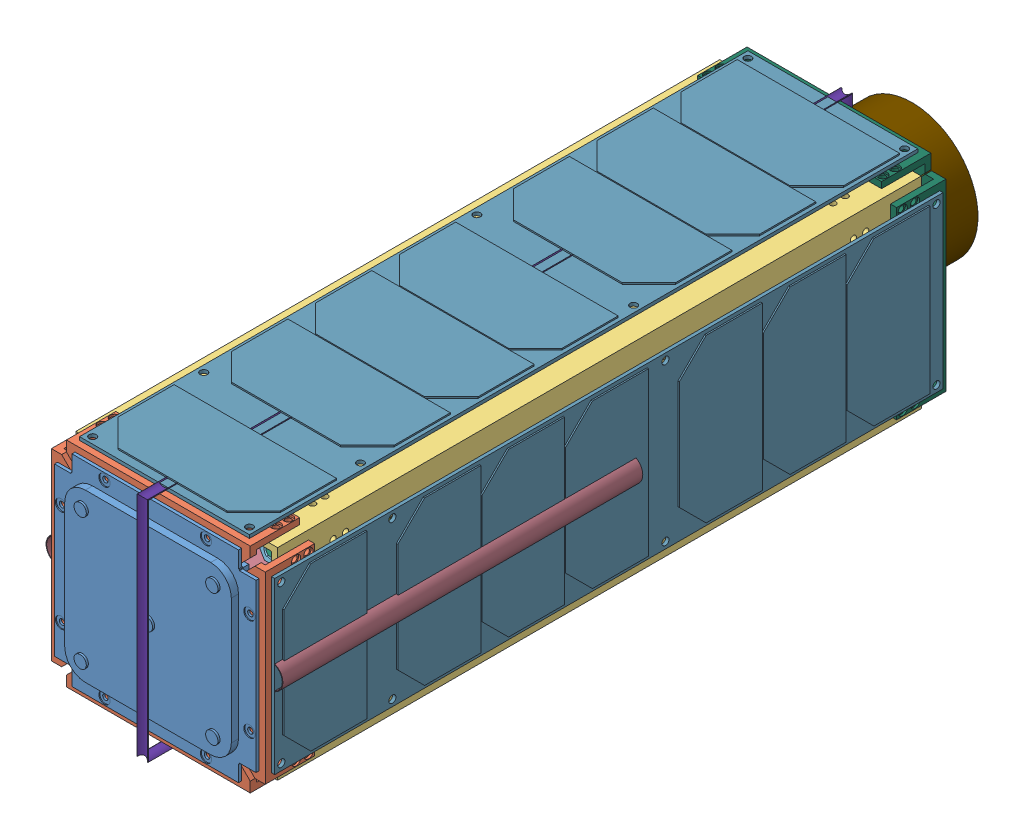
SolidWorks assembly RADIO Deconstructed2, configuration Default. Lengths in mm.
Overall size (115.59 110.99 374.49).
77 component instances, 18 part files, 143 mates.
Components (placement in the parent):
- Nanocom Antenna-1: Nanocom Antenna [Default] at (54.7327 27.087 80.9297) size (98 98 11)
- Top Sipport-1: Top Sipport [Default] at (83.9034 50.4516 80.9297) x (0 -1 0) z (0 0 -1) size (89.4 11 24)
- Top Sipport-2: Top Sipport [Default] at (-15.8818 37.5538 80.9297) x (0 1 0) z (0 0 -1) size (89.4 11 24)
- Top Sipport-3: Top Sipport [Default] at (27.5619 93.8953 80.9297) x (1 0 0) z (0 0 -1) size (89.4 11 24)
- Top Sipport-4: Top Sipport [Default] at (40.4598 -5.8899 80.9297) x (-1 0 0) z (0 0 -1) size (89.4 11 24)
- Support-1: Support [Default] at (-14.9892 90.3455 -221.7132) x (0 -1 0) z (1 0 0) size (18 313 15)
- Support-2: Support [Default] at (-12.332 -4.9973 -221.7132) x (1 0 0) z (0 1 0) size (18 313 15)
- Support-3: Support [Default] at (80.3537 93.0027 -221.7132) x (-1 0 0) z (0 -1 0) size (18 313 15)
- Support-4: Support [Default] at (83.0108 -2.3402 -221.7132) x (0 1 0) z (-1 0 0) size (18 313 15)
- Top Plate2-1: Top Plate2 [Default] at (13.317 21.6849 56.9297) x (-1 0 0) z (0 0 -1) size (92 92 23)
- Nut-1: Nut [Default] at (-1.4892 79.5027 56.9297) size (11.55 10 5.32)
- Nut-2: Nut [Default] at (69.5108 8.5027 56.9297) x (0.821931 0.569587 0) z (0 0 1) size (11.55 10 5.32)
- Nut-3: Nut [Default] at (69.5108 79.5027 56.9297) size (11.55 10 5.32)
- Nut-4: Nut [Default] at (-1.4892 8.5027 56.9297) size (11.55 10 5.32)
- Threaded Rod2-1: Threaded Rod2 [Default] at (69.5108 8.5027 -231.0703) size (6.4 7.01 294.26)
- Threaded Rod2-2: Threaded Rod2 [Default] at (-1.4892 8.5027 -231.0703) size (6.4 7.01 294.26)
- Threaded Rod2-3: Threaded Rod2 [Default] at (-1.4892 79.5027 -231.0703) size (6.4 7.01 294.26)
- Threaded Rod2-4: Threaded Rod2 [Default] at (69.5108 79.5027 -231.0703) size (6.4 7.01 294.26)
- Mid Plate-1: Mid Plate [Default] at (4.649 54.0261 25.9297) size (86 86 3)
- Nut-5: Nut [Default] at (-1.4892 8.5027 20.9297) x (0.999286 -0.037791 0) z (0 0 1) size (11.55 10 5.32)
- Nut-6: Nut [Default] at (-1.4892 8.5027 28.9297) size (11.55 10 5.32)
- Nut-7: Nut [Default] at (69.5108 8.5027 28.9297) size (11.55 10 5.32)
- Nut-8: Nut [Default] at (69.5108 8.5027 20.9297) x (0.921379 0.388666 0) z (0 0 1) size (11.55 10 5.32)
- Nut-9: Nut [Default] at (69.5108 79.5027 28.9297) size (11.55 10 5.32)
- Nut-10: Nut [Default] at (-1.4892 79.5027 28.9297) size (11.55 10 5.32)
- Nut-11: Nut [Default] at (69.5108 79.5027 20.9297) x (0.963517 0.267648 0) z (0 0 1) size (11.55 10 5.32)
- Nut-12: Nut [Default] at (-1.4892 79.5027 20.9297) x (0.997929 0.06432 0) z (0 0 1) size (11.55 10 5.32)
- SDR-1: SDR [Default] at (37.1692 34.198 30.9297) size (65 40 16.8)
- TTC Radio-1: TTC Radio [Default] at (48.3672 78.5027 28.9297) x (0 1 0) z (0 0 1) size (19.7 16 5)
- Raspberry Pi-1: Raspberry Pi [Default] at (63.5108 49.6464 -55.0703) size (66 30.48 5)
- TTC Circuit-1: TTC Circuit [Default] at (24.4431 25.9578 10.9297) size (80 50 10)
- Battery-1: Battery [Default] at (21.7415 31.358 -37.0703) size (70.1 42.59 38.1)
- Tape Antenna-3: Tape Antenna [Default] at (-17.3053 44.2096 -97.0703) x (-0.035253 -0.999378 0) z (0 0 1) size (11.67 4.21 175)
- Tape Antenna-4: Tape Antenna [Default] at (85.299 43.4652 -97.0703) x (0.030207 0.999544 0) z (0 0 1) size (11.67 4.21 175)
- Mid Plate-2: Mid Plate [Default] at (4.649 54.0261 7.9297) size (86 86 3)
- Nut-13: Nut [Default] at (-1.4892 8.5027 10.9297) size (11.55 10 5.32)
- Nut-14: Nut [Default] at (69.5108 79.5027 10.9297) size (11.55 10 5.32)
- Nut-15: Nut [Default] at (-1.4892 8.5027 2.9297) size (11.55 10 5.32)
- Nut-16: Nut [Default] at (-1.4892 79.5027 10.9297) size (11.55 10 5.32)
- Nut-17: Nut [Default] at (-1.4892 79.5027 2.9297) size (11.55 10 5.32)
- Nut-18: Nut [Default] at (69.5108 8.5027 2.9297) size (11.55 10 5.32)
- Nut-19: Nut [Default] at (69.5108 8.5027 10.9297) size (11.55 10 5.32)
- Nut-20: Nut [Default] at (69.5108 79.5027 2.9297) size (11.55 10 5.32)
- Mid Plate-3: Mid Plate [Default] at (4.649 54.0261 -40.0703) size (86 86 3)
- Nut-21: Nut [Default] at (69.5108 79.5027 -37.0703) size (11.55 10 5.32)
- Nut-22: Nut [Default] at (-1.4892 8.5027 -40.0703) x (-0.923728 -0.383049 0) z (0 0 -1) size (11.55 10 5.32)
- Nut-23: Nut [Default] at (-1.4892 79.5027 -40.0703) x (-0.923728 -0.383049 0) z (0 0 -1) size (11.55 10 5.32)
- Nut-24: Nut [Default] at (69.5108 8.5027 -37.0703) size (11.55 10 5.32)
- Nut-25: Nut [Default] at (69.5108 79.5027 -40.0703) x (-0.923728 -0.383049 0) z (0 0 -1) size (11.55 10 5.32)
- Nut-26: Nut [Default] at (69.5108 8.5027 -40.0703) x (-0.923728 -0.383049 0) z (0 0 -1) size (11.55 10 5.32)
- Nut-27: Nut [Default] at (-1.4892 8.5027 -37.0703) size (11.55 10 5.32)
- Nut-28: Nut [Default] at (-1.4892 79.5027 -37.0703) size (11.55 10 5.32)
- Nut-29: Nut [Default] at (-1.4892 8.5027 -63.0703) size (11.55 10 5.32)
- Nut-30: Nut [Default] at (69.5108 79.5027 -63.0703) size (11.55 10 5.32)
- Nut-31: Nut [Default] at (69.5108 8.5027 -63.0703) size (11.55 10 5.32)
- Nut-32: Nut [Default] at (-1.4892 8.5027 -55.0703) size (11.55 10 5.32)
- Nut-33: Nut [Default] at (-1.4892 79.5027 -55.0703) size (11.55 10 5.32)
- Nut-34: Nut [Default] at (69.5108 8.5027 -55.0703) size (11.55 10 5.32)
- Nut-35: Nut [Default] at (-1.4892 79.5027 -63.0703) size (11.55 10 5.32)
- Nut-36: Nut [Default] at (69.5108 79.5027 -55.0703) size (11.55 10 5.32)
- Mid Plate-4: Mid Plate [Default] at (4.649 54.0261 -58.0703) size (86 86 3)
- Top Plate2-2: Top Plate2 [Default] at (54.7047 21.6849 -226.0703) size (92 92 23)
- Nut-37: Nut [Default] at (69.5108 8.5027 -226.0703) x (-0.923728 -0.383049 0) z (0 0 -1) size (11.55 10 5.32)
- Nut-38: Nut [Default] at (69.5108 79.5027 -226.0703) x (-0.923728 -0.383049 0) z (0 0 -1) size (11.55 10 5.32)
- Nut-39: Nut [Default] at (-1.4892 8.5027 -226.0703) x (-0.923728 -0.383049 0) z (0 0 -1) size (11.55 10 5.32)
- Nut-40: Nut [Default] at (-1.4892 79.5027 -226.0703) x (-0.923728 -0.383049 0) z (0 0 -1) size (11.55 10 5.32)
- 3U Panel-1: 3U Panel [Default] at (-17.9892 -8.6653 1.9441) x (0 -1 0) z (-1 0 0) size (82.6 325 2.3)
- 3U Panel-5: 3U Panel [Default] at (86.6788 -7.9973 1.9441) x (1 0 0) z (0 -1 0) size (82.6 325 2.3)
- 3U Panel-6: 3U Panel [Default] at (86.0108 96.6707 1.9441) x (0 1 0) z (1 0 0) size (82.6 325 2.3)
- 3U Panel-7: 3U Panel [Default] at (-18.6571 96.0027 1.9441) x (-1 0 0) z (0 1 0) size (82.6 325 2.3)
- Top Support Solar Panel-1: Top Support Solar Panel [Default] at (27.5619 -3.8899 -250.0703) size (89.4 13 24)
- Top Support Solar Panel-2: Top Support Solar Panel [Default] at (81.9034 37.5538 -250.0703) x (0 1 0) z (0 0 1) size (89.4 13 24)
- Top Support Solar Panel-3: Top Support Solar Panel [Default] at (40.4598 91.8953 -250.0703) x (-1 0 0) z (0 0 1) size (89.4 13 24)
- Top Support Solar Panel-4: Top Support Solar Panel [Default] at (-13.8818 50.4516 -250.0703) x (0 -1 0) z (0 0 1) size (89.4 13 24)
- 1U Panel-1: 1U Panel [Default] at (10.1282 49.1305 -250.0703) x (-1 0 0) z (0 0 -1) size (98 98 2.3)
- Undeployed Boom-1: Undeployed Boom [Default] at (33.6808 70.7812 -106.8653) x (0 0 -1) z (1 0 0) size (342.69 110.69 5.53)
- Mass-1: Mass [Default] at (33.6036 44.7293 -286.0703) size (64 64 36)
Mates (geometry in assembly coordinates):
- Coincident1: coincident: circle of Nanocom Antenna-1; circle of Top Sipport-4
- Coincident2: coincident: circle of Nanocom Antenna-1; circle of Top Sipport-4
- Coincident3: coincident: circle of Nanocom Antenna-1; circle of Top Sipport-2
- Coincident4: coincident: circle of Nanocom Antenna-1; circle of Top Sipport-2
- Coincident5: coincident: circle of Nanocom Antenna-1; circle of Top Sipport-3
- Coincident6: coincident: circle of Nanocom Antenna-1; circle of Top Sipport-3
- Coincident7: coincident: circle of Nanocom Antenna-1; circle of Top Sipport-1
- Coincident8: coincident: circle of Nanocom Antenna-1; circle of Top Sipport-1
- Coincident9: coincident: circle of Top Sipport-2; circle of Support-1
- Coincident10: coincident: circle of Top Sipport-3; circle of Support-1
- Coincident11: coincident: circle of Top Sipport-3; circle of Support-3
- Coincident12: coincident: circle of Top Sipport-1; circle of Support-3
- Coincident13: coincident: circle of Top Sipport-2; circle of Support-2
- Coincident14: coincident: circle of Top Sipport-4; circle of Support-2
- Coincident16: coincident: circle of Top Sipport-4; circle of Support-4
- Coincident17: coincident: circle of Top Sipport-1; circle of Support-4
- Coincident20: coincident: circle of Support-1; circle of Top Plate2-1
- Coincident21: coincident: circle of Support-2; circle of Top Plate2-1
- Coincident22: coincident: circle of Top Plate2-1; circle of Nut-3
- Coincident23: coincident: circle of Top Plate2-1; circle of Nut-1
- Coincident24: coincident: circle of Top Plate2-1; circle of Nut-4
- Coincident25: coincident: circle of Top Plate2-1; circle of Nut-2
- Concentric1: concentric: circle of Top Plate2-1; circle of Threaded Rod2-1
- Coincident26: coincident: plane of Nut-2 through (69.5108 8.5027 61.9297) normal (0 0 1); plane of Threaded Rod2-1 through (69.5108 8.5027 61.9297) normal (0 0 1)
- Concentric2: concentric: circle of Top Plate2-1; circle of Threaded Rod2-4
- Coincident27: coincident: plane of Nut-3 through (69.5108 79.5027 61.9297) normal (0 0 1); plane of Threaded Rod2-4 through (69.5108 79.5027 61.9297) normal (0 0 1)
- Concentric3: concentric: circle of Top Plate2-1; circle of Threaded Rod2-2
- Coincident28: coincident: plane of Nut-4 through (-1.4892 8.5027 61.9297) normal (0 0 1); plane of Threaded Rod2-2 through (-1.4892 8.5027 61.9297) normal (0 0 1)
- Concentric4: concentric: circle of Top Plate2-1; circle of Threaded Rod2-3
- Coincident29: coincident: plane of Nut-1 through (-1.4892 79.5027 61.9297) normal (0 0 1); plane of Threaded Rod2-3 through (-1.4892 79.5027 61.9297) normal (0 0 1)
- Concentric5: concentric: circle of Threaded Rod2-4; circle of Mid Plate-1
- Concentric6: concentric: circle of Threaded Rod2-2; circle of Mid Plate-1
- Concentric7: concentric: circle of Threaded Rod2-2; circle of Nut-6
- Coincident30: coincident: plane of Mid Plate-1 through (4.649 54.0261 28.9297) normal (0 0 1); plane of Nut-6 through (-1.4892 8.5027 28.9297) normal (0 0 -1)
- Concentric8: concentric: circle of Threaded Rod2-2; circle of Nut-5
- Coincident31: coincident: plane of Mid Plate-1 through (4.649 54.0261 25.9297) normal (0 0 -1); plane of Nut-5 through (-1.4892 8.5027 25.9297) normal (0 0 1)
- Concentric9: concentric: circle of Threaded Rod2-1; circle of Nut-7
- Coincident32: coincident: plane of Mid Plate-1 through (4.649 54.0261 28.9297) normal (0 0 1); plane of Nut-7 through (69.5108 8.5027 28.9297) normal (0 0 -1)
- Concentric10: concentric: circle of Threaded Rod2-1; circle of Nut-8
- Coincident33: coincident: plane of Mid Plate-1 through (4.649 54.0261 25.9297) normal (0 0 -1); plane of Nut-8 through (69.5108 8.5027 25.9297) normal (0 0 1)
- Concentric11: concentric: circle of Threaded Rod2-4; circle of Nut-9
- Coincident34: coincident: plane of Mid Plate-1 through (4.649 54.0261 28.9297) normal (0 0 1); plane of Nut-9 through (69.5108 79.5027 28.9297) normal (0 0 -1)
- Concentric12: concentric: circle of Threaded Rod2-3; circle of Nut-10
- Coincident35: coincident: plane of Mid Plate-1 through (4.649 54.0261 28.9297) normal (0 0 1); plane of Nut-10 through (-1.4892 79.5027 28.9297) normal (0 0 -1)
- Concentric13: concentric: circle of Threaded Rod2-4; circle of Nut-11
- Coincident36: coincident: plane of Mid Plate-1 through (4.649 54.0261 25.9297) normal (0 0 -1); plane of Nut-11 through (69.5108 79.5027 25.9297) normal (0 0 1)
- Concentric14: concentric: circle of Threaded Rod2-3; circle of Nut-12
- Coincident37: coincident: plane of Mid Plate-1 through (4.649 54.0261 25.9297) normal (0 0 -1); plane of Nut-12 through (-1.4892 79.5027 25.9297) normal (0 0 1)
- Distance1: distance = 25 mm: plane of Mid Plate-1 through (4.649 54.0261 28.9297) normal (0 0 1); plane of Top Plate2-1 through (13.317 21.6849 53.9297) normal (0 0 -1)
- Coincident39: coincident: plane of Mid Plate-1 through (4.649 54.0261 28.9297) normal (0 0 1); plane of SDR-1 through (37.1692 34.198 28.9297) normal (0 0 -1)
- Distance4: distance = 12 mm: line of SDR-1 through (65.0108 16.0027 28.9297) axis (0 1 0); line of Mid Plate-1 through (77.0108 4.0027 28.9297) axis (0 1 0)
- Distance5: distance = 15 mm: line of SDR-1 through (0.0108 16.0027 28.9297) axis (1 0 0); line of Mid Plate-1 through (-5.9892 1.0027 28.9297) axis (1 0 0)
- Coincident46: coincident: plane of Mid Plate-1 through (4.649 54.0261 28.9297) normal (0 0 1); plane of TTC Radio-1 through (48.3672 78.5027 28.9297) normal (0 0 -1)
- Distance8: distance = 20 mm: plane of TTC Radio-1 through (57.0108 78.5027 30.9297) normal (1 0 0); plane of Mid Plate-1 through (77.0108 4.0027 28.9297) normal (1 0 0)
- Distance9: distance = 5 mm: plane of TTC Radio-1 through (48.3672 82.0027 30.9297) normal (0 1 0); line of Mid Plate-1 through (74.0108 87.0027 28.9297) axis (-1 0 0)
- Coincident53: coincident: plane of TTC Circuit-1 through (24.4431 25.9578 10.9297) normal (0 0 -1); plane of Mid Plate-2 through (4.649 54.0261 10.9297) normal (0 0 1)
- Distance10: distance = 5 mm: line of TTC Circuit-1 through (-4.4066 66.0027 12.9297) axis (0 -1 0); line of Mid Plate-2 through (-8.9892 84.0027 10.9297) axis (0 -1 0)
- Distance13: distance = 21.095 mm: line of TTC Circuit-1 through (75.5934 66.0027 12.9297) axis (-1 0 0); line of Mid Plate-2 through (74.0108 87.0027 10.9297) axis (-1 0 0)
- Concentric16: concentric: circle of Threaded Rod2-2; circle of Mid Plate-2
- Concentric18: concentric: circle of Threaded Rod2-4; circle of Mid Plate-2
- Concentric19: concentric: circle of Threaded Rod2-4; circle of Nut-14
- Coincident59: coincident: plane of Mid Plate-2 through (4.649 54.0261 10.9297) normal (0 0 1); plane of Nut-14 through (69.5108 79.5027 10.9297) normal (0 0 -1)
- Concentric20: concentric: circle of Threaded Rod2-4; circle of Nut-20
- Coincident60: coincident: plane of Mid Plate-2 through (4.649 54.0261 7.9297) normal (0 0 -1); plane of Nut-20 through (69.5108 79.5027 7.9297) normal (0 0 1)
- Concentric21: concentric: circle of Threaded Rod2-1; circle of Nut-19
- Coincident61: coincident: plane of Mid Plate-2 through (4.649 54.0261 10.9297) normal (0 0 1); plane of Nut-19 through (69.5108 8.5027 10.9297) normal (0 0 -1)
- Concentric22: concentric: circle of Threaded Rod2-1; circle of Nut-18
- Coincident62: coincident: plane of Mid Plate-2 through (4.649 54.0261 7.9297) normal (0 0 -1); plane of Nut-18 through (69.5108 8.5027 7.9297) normal (0 0 1)
- Concentric23: concentric: circle of Threaded Rod2-2; circle of Nut-13
- Coincident63: coincident: plane of Mid Plate-2 through (4.649 54.0261 10.9297) normal (0 0 1); plane of Nut-13 through (-1.4892 8.5027 10.9297) normal (0 0 -1)
- Concentric24: concentric: circle of Threaded Rod2-2; circle of Nut-15
- Coincident64: coincident: plane of Mid Plate-2 through (4.649 54.0261 7.9297) normal (0 0 -1); plane of Nut-15 through (-1.4892 8.5027 7.9297) normal (0 0 1)
- Concentric25: concentric: circle of Threaded Rod2-3; circle of Nut-16
- Coincident65: coincident: plane of Mid Plate-2 through (4.649 54.0261 10.9297) normal (0 0 1); plane of Nut-16 through (-1.4892 79.5027 10.9297) normal (0 0 -1)
- Concentric26: concentric: circle of Threaded Rod2-3; circle of Nut-17
- Coincident66: coincident: plane of Mid Plate-2 through (4.649 54.0261 7.9297) normal (0 0 -1); plane of Nut-17 through (-1.4892 79.5027 7.9297) normal (0 0 1)
- Distance14: distance = 15 mm: plane of Mid Plate-2 through (4.649 54.0261 10.9297) normal (0 0 1); plane of Mid Plate-1 through (4.649 54.0261 25.9297) normal (0 0 -1)
- Coincident68: coincident: circle of Mid Plate-3; circle of Nut-21
- Coincident69: coincident: circle of Mid Plate-3; circle of Nut-24
- Coincident70: coincident: circle of Mid Plate-3; circle of Nut-27
- Coincident71: coincident: circle of Mid Plate-3; circle of Nut-28
- Coincident72: coincident: circle of Mid Plate-3; circle of Nut-25
- Coincident73: coincident: circle of Mid Plate-3; circle of Nut-23
- Coincident74: coincident: circle of Mid Plate-3; circle of Nut-22
- Coincident76: coincident: circle of Mid Plate-3; circle of Nut-26
- Coincident77: coincident: plane of Battery-1 through (21.7415 31.358 -37.0703) normal (0 0 -1); plane of Mid Plate-3 through (4.649 54.0261 -37.0703) normal (0 0 1)
- Distance16: distance = 30 mm: line of Battery-1 through (57.8687 57.4223 -32.0703) axis (-1 0 0); line of Mid Plate-3 through (74.0108 87.0027 -37.0703) axis (-1 0 0)
- Distance17: distance = 15 mm: line of Battery-1 through (62.8687 24.8323 -32.0703) axis (0 1 0); line of Mid Plate-3 through (77.0108 4.0027 -37.0703) axis (0 1 0)
- Concentric27: concentric: circle of Threaded Rod2-2; circle of Nut-27
- Concentric28: concentric: circle of Threaded Rod2-4; circle of Nut-21
- Distance18: distance = 45 mm: plane of Mid Plate-3 through (4.649 54.0261 -37.0703) normal (0 0 1); plane of Mid Plate-2 through (4.649 54.0261 7.9297) normal (0 0 -1)
- Coincident83: coincident: plane of Raspberry Pi-1 through (63.5108 49.6464 -55.0703) normal (0 0 -1); plane of Mid Plate-4 through (4.649 54.0261 -55.0703) normal (0 0 1)
- Distance19: distance = 30 mm: line of Raspberry Pi-1 through (67.0108 57.0027 -55.0703) axis (-1 0 0); line of Mid Plate-4 through (74.0108 87.0027 -55.0703) axis (-1 0 0)
- Distance20: distance = 10 mm: line of Raspberry Pi-1 through (67.0108 26.5227 -55.0703) axis (0 1 0); line of Mid Plate-4 through (77.0108 4.0027 -55.0703) axis (0 1 0)
- Concentric29: concentric: circle of Nut-29; circle of Mid Plate-4
- Coincident87: coincident: plane of Nut-29 through (-1.4892 8.5027 -58.0703) normal (0 0 1); plane of Mid Plate-4 through (4.649 54.0261 -58.0703) normal (0 0 -1)
- Concentric30: concentric: circle of Nut-31; circle of Mid Plate-4
- Coincident89: coincident: plane of Nut-31 through (69.5108 8.5027 -58.0703) normal (0 0 1); plane of Mid Plate-4 through (4.649 54.0261 -58.0703) normal (0 0 -1)
- Concentric31: concentric: circle of Nut-30; circle of Mid Plate-4
- Coincident91: coincident: plane of Nut-30 through (69.5108 79.5027 -58.0703) normal (0 0 1); plane of Mid Plate-4 through (4.649 54.0261 -58.0703) normal (0 0 -1)
- Concentric32: concentric: circle of Nut-35; circle of Mid Plate-4
- Coincident93: coincident: plane of Nut-35 through (-1.4892 79.5027 -58.0703) normal (0 0 1); plane of Mid Plate-4 through (4.649 54.0261 -58.0703) normal (0 0 -1)
- Coincident94: coincident: circle of Nut-33; circle of Mid Plate-4
- Coincident95: coincident: circle of Nut-32; circle of Mid Plate-4
- Coincident96: coincident: circle of Nut-36; circle of Mid Plate-4
- Coincident97: coincident: circle of Nut-34; circle of Mid Plate-4
- Concentric33: concentric: circle of Threaded Rod2-2; circle of Nut-29
- Concentric34: concentric: circle of Threaded Rod2-3; circle of Nut-35
- Distance21: distance = 15 mm: plane of Mid Plate-4 through (4.649 54.0261 -55.0703) normal (0 0 1); plane of Mid Plate-3 through (4.649 54.0261 -40.0703) normal (0 0 -1)
- Coincident100: coincident: circle of Top Plate2-2; circle of Nut-37
- Coincident101: coincident: circle of Top Plate2-2; circle of Nut-39
- Coincident102: coincident: circle of Top Plate2-2; circle of Nut-38
- Coincident103: coincident: circle of Top Plate2-2; circle of Nut-40
- Concentric35: concentric: circle of Threaded Rod2-3; circle of Top Plate2-2
- Concentric36: concentric: circle of Threaded Rod2-4; circle of Top Plate2-2
- Coincident104: coincident: plane of Threaded Rod2-4 through (69.5108 79.5027 -231.0703) normal (0 0 -1); plane of Nut-38 through (69.5108 79.5027 -231.0703) normal (0 0 -1)
- Coincident123: coincident: circle of Top Sipport-2; circle of 3U Panel-1
- Coincident124: coincident: circle of Top Sipport-2; circle of 3U Panel-1
- Coincident125: coincident: circle of Top Sipport-4; circle of 3U Panel-5
- Coincident126: coincident: circle of Top Sipport-4; circle of 3U Panel-5
- Coincident127: coincident: circle of Top Sipport-3; circle of 3U Panel-7
- Coincident128: coincident: circle of Top Sipport-3; circle of 3U Panel-7
- Coincident129: coincident: circle of Top Sipport-1; circle of 3U Panel-6
- Coincident130: coincident: circle of Top Sipport-1; circle of 3U Panel-6
- Coincident131: coincident: point of Tape Antenna-4; line of 3U Panel-6 through (87.6108 85.3027 77.9297) axis (0 -1 0)
- Coincident132: coincident: point of Tape Antenna-4; line of 3U Panel-6 through (87.6108 85.3027 77.9297) axis (0 -1 0)
- Parallel16: parallel: line of Support-4 through (83.0108 -4.9973 -241.0703) axis (0 0 1); line of Tape Antenna-4 through (87.7209 37.6494 77.9297) axis (0 0 -1)
- Coincident137: coincident: point of Tape Antenna-3; line of 3U Panel-1 through (-19.5892 2.7027 77.9297) axis (0 1 0)
- Coincident138: coincident: point of Tape Antenna-3; line of 3U Panel-1 through (-19.5892 2.7027 77.9297) axis (0 1 0)
- Parallel19: parallel: line of Tape Antenna-3 through (-19.6978 50.0375 77.9297) axis (0 0 -1); line of 3U Panel-1 through (-19.5892 85.3027 77.9297) axis (0 0 -1)
- Coincident140: coincident: circle of 3U Panel-6; circle of Top Support Solar Panel-2
- Coincident141: coincident: circle of 3U Panel-6; circle of Top Support Solar Panel-2
- Coincident142: coincident: circle of 3U Panel-5; circle of Top Support Solar Panel-1
- Coincident143: coincident: circle of 3U Panel-5; circle of Top Support Solar Panel-1
- Coincident144: coincident: circle of 3U Panel-1; circle of Top Support Solar Panel-4
- Coincident145: coincident: circle of 3U Panel-1; circle of Top Support Solar Panel-4
- Coincident146: coincident: circle of 3U Panel-7; circle of Top Support Solar Panel-3
- Coincident147: coincident: circle of 3U Panel-7; circle of Top Support Solar Panel-3
- Coincident148: coincident: circle of Top Support Solar Panel-3; circle of 1U Panel-1
- Coincident149: coincident: circle of Top Support Solar Panel-1; circle of 1U Panel-1
- Parallel20: parallel: line of Support-3 through (83.0108 93.0027 -241.0703) axis (0 0 1); line of Undeployed Boom-1 through (30.9528 97.7265 -106.8653) axis (0 0 -1)
- Tangent4: tangent: cylinder of Undeployed Boom-1 through (33.6808 -12.8247 90.615) axis (0 1 0) radius 3.6853; plane of Nanocom Antenna-1 through (34.0108 44.0027 86.9297) normal (0 0 1)
- Coincident152: coincident: plane of 1U Panel-1 through (10.1282 49.1305 -250.0703) normal (0 0 1); plane of Mass-1 through (33.6036 44.7293 -250.0703) normal (0 0 1)
